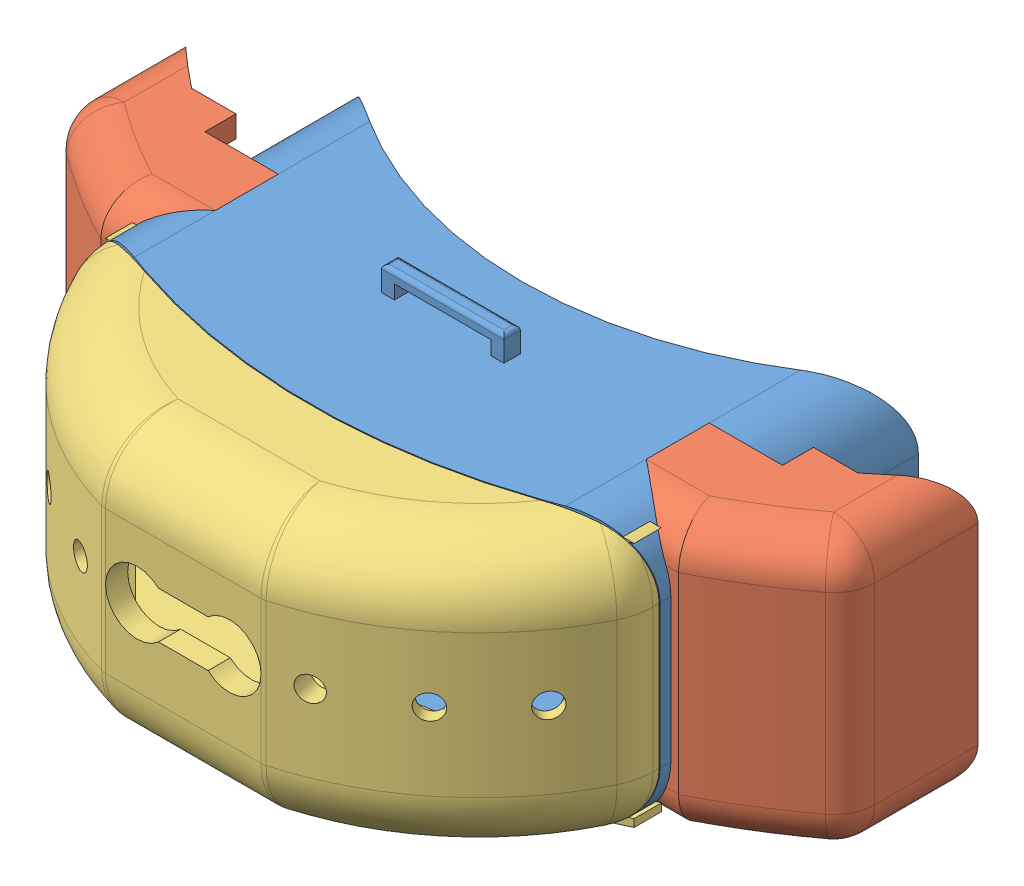
SolidWorks assembly Headset Assembly, configuration Default. Lengths in mm.
Overall size (244.98 94.83 143.29).
4 component instances, 3 part files, 12 mates.
Components (placement in the parent):
- housing-1: housing [Default] at (-11.625 -29.1076 -23.9946) size (189.23 92.46 102.93)
- speaker_wing-1: speaker_wing [Default] at (-14.0263 55.7284 19.2152) size (57.21 84.84 61.11)
- speaker_wing-2: speaker_wing [Default] at (-9.2238 -29.1076 19.2152) x (-1 0 0) z (0 0 1) size (57.21 84.84 61.11)
- front cover-2: front cover [Default] at (-11.625 -29.1076 124.7958) x (-1 0 0) z (0 0 -1) size (173.99 89.59 68.36)
Mates (geometry in assembly coordinates):
- Coincident1: coincident anti-aligned: plane of housing-1 through (-98.62 -29.1076 77.6054) normal (-1 0 0); plane of speaker_wing-1 through (-98.62 -8.7876 -32.2105) normal (1 0 0)
- Parallel1: parallel aligned: plane of housing-1 through (75.37 -29.1076 77.6054) normal (0 -1 0); plane of speaker_wing-1 through (-14.0263 -29.1076 -118.4892) normal (0 -1 0)
- Coincident3: coincident aligned: plane of housing-1 through (75.37 55.7284 77.6054) normal (0 1 0); plane of speaker_wing-1 through (-14.0263 55.7284 -118.4892) normal (0 1 0)
- Coincident8: coincident aligned: plane of housing-1 through (75.37 55.7284 77.6054) normal (0 1 0); plane of speaker_wing-2 through (-9.2238 55.7284 -118.4892) normal (0 1 0)
- Coincident9: coincident anti-aligned: plane of housing-1 through (75.37 -29.1076 77.6054) normal (1 0 0); plane of speaker_wing-2 through (75.37 35.4084 -32.2105) normal (-1 0 0)
- Coincident10: coincident aligned: plane of housing-1 through (-98.62 -29.1076 77.6054) normal (-1 0 0); plane of ? through (-98.62 55.7284 122.5843) normal (-1 0 0)
- Parallel3: parallel aligned: line of speaker_wing-1 through (-134.1165 43.0284 31.2547) axis (0 0 -1); line of ? through (-98.62 35.4084 128.9343) axis (0 0 -1)
- Coincident13: coincident aligned: plane of housing-1 through (75.37 55.7284 77.6054) normal (0 1 0); plane of ? through (-11.625 55.7284 91.3427) normal (0 1 0)
- Coincident14: coincident anti-aligned: line of speaker_wing-1 through (-78.3 55.7284 20.4444) axis (-1 0 0); line of speaker_wing-2 through (55.05 55.7284 20.4444) axis (1 0 0)
- Coincident15: coincident aligned: plane of housing-1 through (75.37 55.7284 77.6054) normal (0 1 0); plane of front cover-2 through (-11.625 55.7284 25.0251) normal (0 1 0)
- Parallel4: parallel: line of housing-1 through (7.298 62.0784 36.2034) axis (-1 0 0); line of front cover-2 through (-35.7051 55.7284 116.4145) axis (1 0 0)
- Coincident17: coincident aligned: plane of housing-1 through (75.37 -29.1076 77.6054) normal (1 0 0); plane of front cover-2 through (75.37 55.7284 62.6167) normal (1 0 0)
